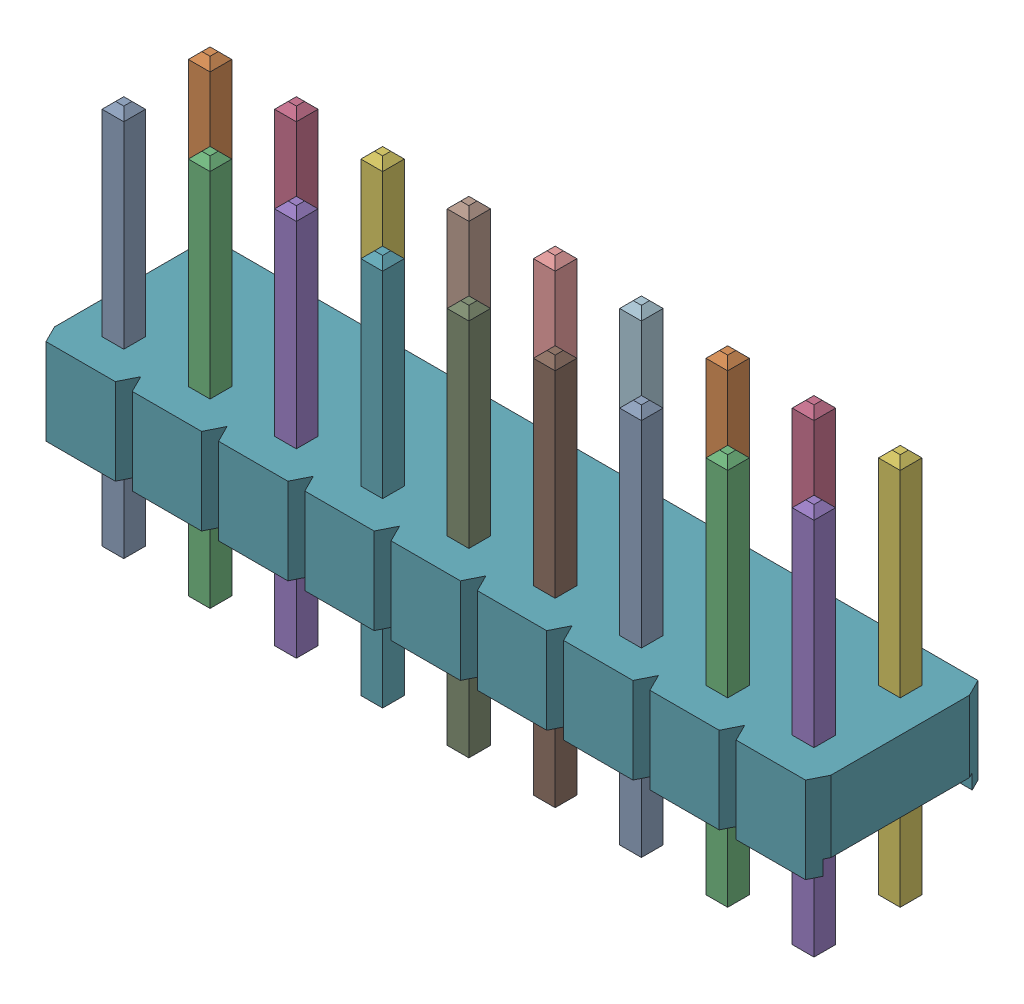
SolidWorks assembly DEFAULT, configuration Predeterminado. Lengths in mm.
Overall size (22.86 11.54 5.08).
19 component instances, 2 part files, 0 mates.
Components (placement in the parent):
- DEFAULT-1: DEFAULT [Predeterminado] at (-10.16 1.5 0) x (1 0 0) z (0 -1 0) size (0.64 0.64 11.54)
- DEFAULT-2: DEFAULT [Predeterminado] at (-10.16 1.5 -2.54) x (1 0 0) z (0 -1 0) size (0.64 0.64 11.54)
- DEFAULT-3: DEFAULT [Predeterminado] at (-7.62 1.5 0) x (1 0 0) z (0 -1 0) size (0.64 0.64 11.54)
- DEFAULT-4: DEFAULT [Predeterminado] at (-7.62 1.5 -2.54) x (1 0 0) z (0 -1 0) size (0.64 0.64 11.54)
- DEFAULT-5: DEFAULT [Predeterminado] at (-5.08 1.5 0) x (1 0 0) z (0 -1 0) size (0.64 0.64 11.54)
- DEFAULT-6: DEFAULT [Predeterminado] at (-5.08 1.5 -2.54) x (1 0 0) z (0 -1 0) size (0.64 0.64 11.54)
- DEFAULT-7: DEFAULT [Predeterminado] at (-2.54 1.5 0) x (1 0 0) z (0 -1 0) size (0.64 0.64 11.54)
- DEFAULT-8: DEFAULT [Predeterminado] at (-2.54 1.5 -2.54) x (1 0 0) z (0 -1 0) size (0.64 0.64 11.54)
- DEFAULT-9: DEFAULT [Predeterminado] at (0 1.5 0) x (1 0 0) z (0 -1 0) size (0.64 0.64 11.54)
- DEFAULT-10: DEFAULT [Predeterminado] at (0 1.5 -2.54) x (1 0 0) z (0 -1 0) size (0.64 0.64 11.54)
- DEFAULT-11: DEFAULT [Predeterminado] at (2.54 1.5 0) x (1 0 0) z (0 -1 0) size (0.64 0.64 11.54)
- DEFAULT-12: DEFAULT [Predeterminado] at (2.54 1.5 -2.54) x (1 0 0) z (0 -1 0) size (0.64 0.64 11.54)
- DEFAULT-13: DEFAULT [Predeterminado] at (5.08 1.5 0) x (1 0 0) z (0 -1 0) size (0.64 0.64 11.54)
- DEFAULT-14: DEFAULT [Predeterminado] at (5.08 1.5 -2.54) x (1 0 0) z (0 -1 0) size (0.64 0.64 11.54)
- DEFAULT-15: DEFAULT [Predeterminado] at (7.62 1.5 0) x (1 0 0) z (0 -1 0) size (0.64 0.64 11.54)
- DEFAULT-16: DEFAULT [Predeterminado] at (7.62 1.5 -2.54) x (1 0 0) z (0 -1 0) size (0.64 0.64 11.54)
- DEFAULT-17: DEFAULT [Predeterminado] at (10.16 1.5 0) x (1 0 0) z (0 -1 0) size (0.64 0.64 11.54)
- DEFAULT-18: DEFAULT [Predeterminado] at (10.16 1.5 -2.54) x (1 0 0) z (0 -1 0) size (0.64 0.64 11.54)
- DEFAULT-1-1: DEFAULT-1 [Predeterminado] at origin size (22.86 2.54 5.08)
